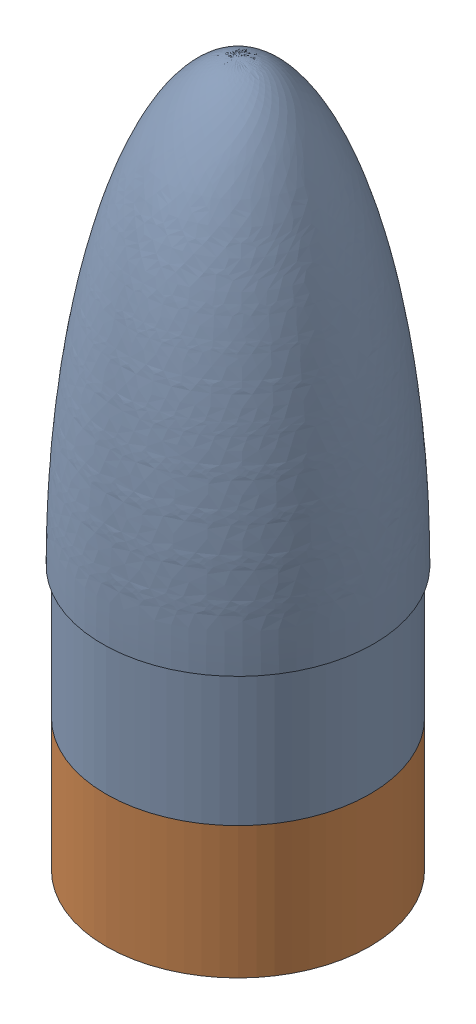
SolidWorks assembly NoseconeWithCup, configuration Default. Lengths in mm.
Overall size (156.72 406.4 156.72).
2 component instances, 2 part files, 1 mates.
Components (placement in the parent):
- NoseconeWithCup-1: NoseconeWithCup [Default] at (-135.4195 -97.4448 77.2642) size (156.72 330.2 156.72)
- Cup-1: Cup [Default] at (-135.4195 -173.6448 77.2642) x (1 0 0) z (0 -1 0) size (152.4 152.4 76.2)
Mates (geometry in assembly coordinates):
- Coincident1: coincident aligned: circle of NoseconeWithCup-1; circle of Cup-1
